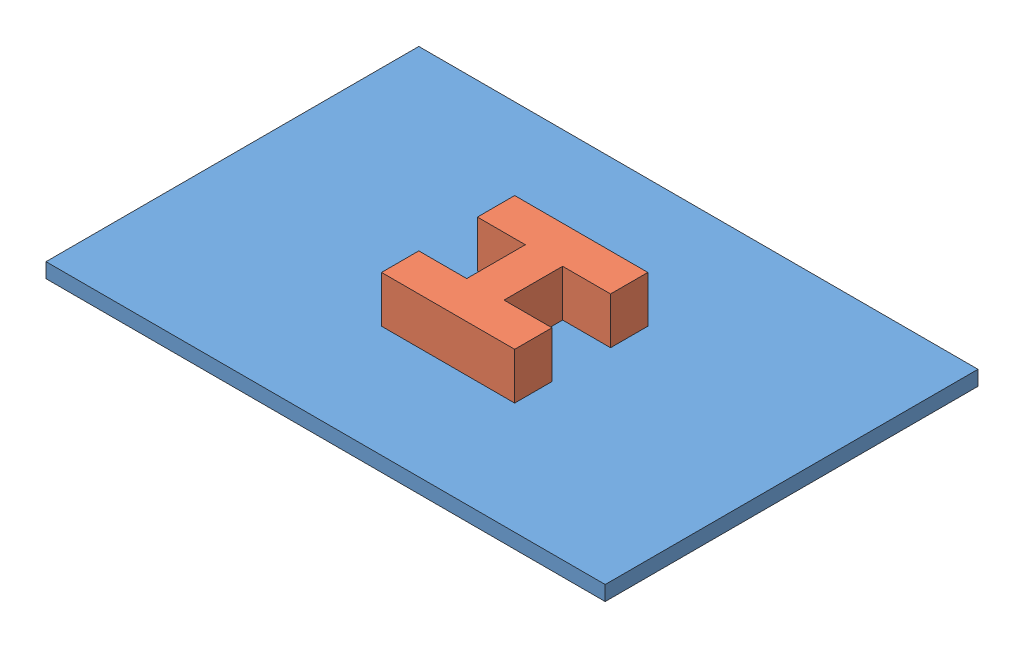
SolidWorks assembly cubebottom, configuration Default. Lengths in mm.
Overall size (60 6.59 40).
2 component instances, 2 part files, 3 mates.
Components (placement in the parent):
- protoboard-1: protoboard [Default] at (17.8486 30.0373 48.7812) size (60 1.59 40)
- cubebottompins-1: cubebottompins [Default] at (18.9924 31.6248 49.6374) size (14.29 5 14.29)
Mates (geometry in assembly coordinates):
- Distance1: distance = 12 mm: line of cubebottompins-1 through (11.8486 31.6248 56.7812) axis (1 0 0); line of protoboard-1 through (-12.1514 31.6248 68.7812) axis (1 0 0)
- Coincident4: coincident: plane of protoboard-1 through (17.8486 31.6248 48.7812) normal (0 1 0); plane of cubebottompins-1 through (17.4831 31.6248 49.6374) normal (0 -1 0)
- Distance3: distance = 24 mm: line of cubebottompins-1 through (11.8486 31.6248 52.7812) axis (0 0 1); line of protoboard-1 through (-12.1514 31.6248 28.7812) axis (0 0 1)
